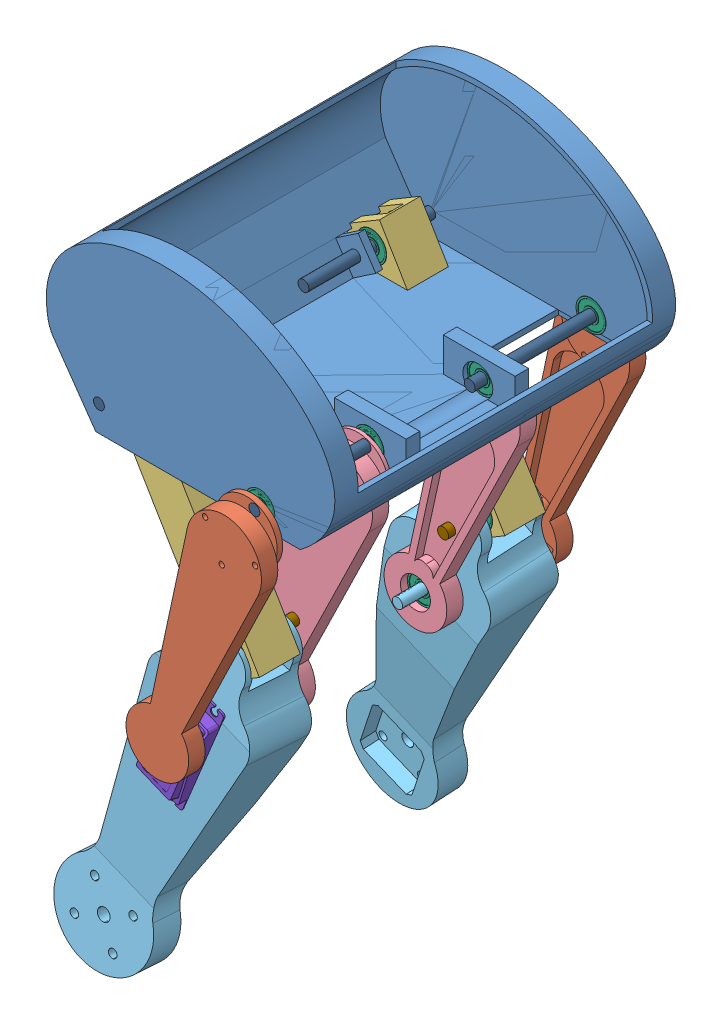
SolidWorks assembly assem2, configuration Default. Lengths in mm.
Overall size (235.71 499.1 282).
34 component instances, 10 part files, 44 mates.
Components (placement in the parent):
- head2-1: head2 [Default] at (68.1792 80.6279 71.4777) size (224.14 133.43 250)
- upleg_outer-1: upleg_outer [Default] at (100.6037 54.0653 55.4777) x (0.325909 0.945401 0) z (0 0 1) size (209.32 55 16)
- rod2-1: rod2 [Default] at (40.0387 -3.846 101.9168) x (-0.511098 0.859523 0) z (0.859523 0.511098 0) size (180 30 30)
- upleg_inner-1: upleg_inner [Default] at (100.4545 54.0549 135.5333) x (0.329052 0.944312 0) z (0 0 1) size (209.32 55 16)
- upleg_inner-2: upleg_inner [Default] at (100.4545 54.0549 255.937) x (0.329052 0.944312 0) z (0 0 -1) size (209.32 55 16)
- lowerleg2-1: lowerleg2 [Default] at (-10.3698 -235.5061 117.5405) x (-0.924718 0.380654 0) z (0.042832 0.104052 -0.993649) size (78.06 261.21 79.23)
- Bearing, Sealed, 608-2RS, 22X8X7-1: Bearing, Sealed, 608-2RS, 22X8X7 [Default] at (54.287 -78.436 247.312) x (0 0 1) z (-0.94306 -0.332623 0) size (7 22 22)
- Bearing, Sealed, 608-2RS, 22X8X7-2: Bearing, Sealed, 608-2RS, 22X8X7 [Default] at (73.7413 -31.1758 118.0588) x (0 0 1) z (0.999634 -0.027042 0) size (7 22 22)
- Bearing, Sealed, 608-2RS, 22X8X7-3: Bearing, Sealed, 608-2RS, 22X8X7 [Default] at (73.7413 -31.1758 94.9338) x (0 0 -1) z (0.30577 0.952105 0) size (7 22 22)
- Bearing, Sealed, 608-2RS, 22X8X7-4: Bearing, Sealed, 608-2RS, 22X8X7 [Default] at (54.287 -78.436 139.0333) x (0 0 -1) z (-0.978141 0.207944 0) size (7 22 22)
- ServoAttacment1-1: ServoAttacment1 [Varsayılan] at (54.8772 -78.5784 63.4777) x (-0.99957 0.029327 0) z (0 0 -1) size (37.5 37.5 6)
- DSSERVO_150kg_80kg_60kg.step-1: DSSERVO_150kg_80kg_60kg.step [Default] at (47.4545 -96.6104 117.1777) x (0.380654 0.924718 0) z (-0.924718 0.380654 0) size (87.5 54.7 30)
- lowerleg2-2: lowerleg2 [Default] at (-10.3698 -235.5061 275.4149) x (0.924718 -0.380654 0) z (0.042832 0.104052 0.993649) size (78.06 261.21 79.23)
- DSSERVO_150kg_80kg_60kg.step-2: DSSERVO_150kg_80kg_60kg.step [Default] at (47.4545 -96.6104 275.7777) x (0.380654 0.924718 0) z (0.924718 -0.380654 0) size (87.5 54.7 30)
- upleg_outer-4: upleg_outer [Default] at (100.6037 54.0653 337.4777) x (0.325909 0.945401 0) z (0 0 -1) size (209.32 55 16)
- ServoAttacment1-2: ServoAttacment1 [Varsayılan] at (54.8772 -78.5784 329.4777) x (-0.99957 0.029327 0) z (0 0 1) size (37.5 37.5 6)
- head2-2: head2 [Default] at (68.1792 80.6279 71.4777) size (224.14 133.43 250)
- ball rod-1: ball rod [Default] at (73.7413 -31.1758 86.7586) x (0.949707 0.31314 0) z (0 0 1) size (8 8 60)
- Bearing, Sealed, 608-2RS, 22X8X7-7: Bearing, Sealed, 608-2RS, 22X8X7 [Default] at (-3.9455 99.4716 94.8088) x (0 0 1) z (-1 0 0) size (7 22 22)
- Bearing, Sealed, 608-2RS, 22X8X7-8: Bearing, Sealed, 608-2RS, 22X8X7 [Default] at (-3.9455 99.4716 118.0588) x (0 0 1) z (-1 0 0) size (7 22 22)
- ball rod2-1: ball rod2 [Default] at (-3.9455 99.4716 71.4777) x (0.674488 -0.738286 0) z (0 0 1) size (8 8 100)
- Bearing, Sealed, 608-2RS, 22X8X7-9: Bearing, Sealed, 608-2RS, 22X8X7 [Default] at (114.0698 93.1279 75.1027) x (0 0 -1) z (0.914822 -0.403858 0) size (7 22 22)
- Bearing, Sealed, 608-2RS, 22X8X7-10: Bearing, Sealed, 608-2RS, 22X8X7 [Default] at (114.0698 93.1279 154.9083) x (0 0 -1) z (0.999997 0.002549 0) size (7 22 22)
- rod2-3: rod2 [Default] at (65.8244 11.4869 291.0386) x (-0.511098 0.859523 0) z (-0.859523 -0.511098 0) size (180 30 30)
- ball rod2-2: ball rod2 [Default] at (-3.9455 99.4716 221.4777) x (0.674488 -0.738286 0) z (0 0 1) size (8 8 100)
- Bearing, Sealed, 608-2RS, 22X8X7-11: Bearing, Sealed, 608-2RS, 22X8X7 [Default] at (54.287 -78.436 253.9221) x (0 0 1) z (0.978141 -0.207944 0) size (7 22 22)
- Bearing, Sealed, 608-2RS, 22X8X7-12: Bearing, Sealed, 608-2RS, 22X8X7 [Default] at (73.7413 -31.1758 274.8965) x (0 0 -1) z (-0.999634 0.027042 0) size (7 22 22)
- ball rod-2: ball rod [Default] at (73.7413 -31.1758 246.1968) x (0.949707 0.31314 0) z (0 0 1) size (8 8 60)
- Bearing, Sealed, 608-2RS, 22X8X7-13: Bearing, Sealed, 608-2RS, 22X8X7 [Default] at (-3.9455 99.4716 298.1465) x (0 0 -1) z (1 0 0) size (7 22 22)
- Bearing, Sealed, 608-2RS, 22X8X7-14: Bearing, Sealed, 608-2RS, 22X8X7 [Default] at (-3.9455 99.4716 274.8965) x (0 0 -1) z (1 0 0) size (7 22 22)
- Bearing, Sealed, 608-2RS, 22X8X7-15: Bearing, Sealed, 608-2RS, 22X8X7 [Default] at (114.0698 93.1279 317.8527) x (0 0 1) z (-0.914822 0.403858 0) size (7 22 22)
- Bearing, Sealed, 608-2RS, 22X8X7-16: Bearing, Sealed, 608-2RS, 22X8X7 [Default] at (114.0698 93.1279 238.0471) x (0 0 1) z (-0.999997 -0.002549 0) size (7 22 22)
- ball rod2-3: ball rod2 [Default] at (114.0698 93.1279 67.4777) x (0.911931 -0.410344 0) z (0 0 1) size (8 8 100)
- ball rod2-4: ball rod2 [Default] at (114.0698 93.1279 225.4777) x (0.911931 -0.410344 0) z (0 0 1) size (8 8 100)
Mates (geometry in assembly coordinates):
- Concentric4: concentric aligned: cylinder of upleg_inner-2 through (54.287 -78.436 255.937) axis (0 0 -1) radius 11; cylinder of Bearing, Sealed, 608-2RS, 22X8X7-1 through (54.287 -78.436 243.812) axis (0 0 -1) radius 4
- Coincident19: coincident aligned: circle of upleg_inner-2; circle of Bearing, Sealed, 608-2RS, 22X8X7-1
- Concentric5: concentric aligned: cylinder of rod2-1 through (73.7413 -31.1758 91.4338) axis (0 0 1) radius 11; cylinder of Bearing, Sealed, 608-2RS, 22X8X7-3 through (73.7413 -31.1758 98.4338) axis (0 0 1) radius 4
- Coincident20: coincident anti-aligned: circle of rod2-1; plane of Bearing, Sealed, 608-2RS, 22X8X7-3 through (64.5773 -28.2328 91.4338) normal (0 0 -1)
- Concentric12: concentric aligned: circle of upleg_inner-2; circle of Bearing, Sealed, 608-2RS, 22X8X7-1
- Concentric23: concentric aligned: cylinder of upleg_inner-1 through (54.287 -78.436 135.5333) axis (0 0 1) radius 11; cylinder of Bearing, Sealed, 608-2RS, 22X8X7-4 through (54.287 -78.436 142.5333) axis (0 0 1) radius 4
- Coincident26: coincident anti-aligned: circle of upleg_inner-1; plane of Bearing, Sealed, 608-2RS, 22X8X7-4 through (52.2856 -87.8506 135.5333) normal (0 0 -1)
- Concentric28: concentric anti-aligned: line of rod2-1 through (73.7413 -31.1758 91.4338) axis (0 0 1); axis of Bearing, Sealed, 608-2RS, 22X8X7-2 through (73.7413 -31.1758 114.8088) axis (0 0 -1)
- Coincident28: coincident aligned: circle of rod2-1; circle of Bearing, Sealed, 608-2RS, 22X8X7-2
- Concentric32: concentric aligned: circle of upleg_outer-1; circle of ServoAttacment1-1
- Coincident44: coincident anti-aligned: plane of lowerleg2-1 through (-10.3698 -235.5061 117.1777) normal (0 0 -1); plane of DSSERVO_150kg_80kg_60kg.step-1 through (47.4545 -96.6104 117.1777) normal (0 0 1)
- Coincident46: coincident anti-aligned: plane of lowerleg2-1 through (73.566 -72.3213 117.1777) normal (-0.380654 -0.924718 0); plane of DSSERVO_150kg_80kg_60kg.step-1 through (71.809 -71.5981 106.4777) normal (0.380654 0.924718 0)
- Coincident47: coincident: line of lowerleg2-1 through (73.566 -72.3213 83.1777) axis (-0.380654 -0.924718 0); plane of DSSERVO_150kg_80kg_60kg.step-1 through (71.7008 -76.8524 106.4777) normal (0.924718 -0.380654 0)
- Coincident53: coincident anti-aligned: plane of ServoAttacment1-1 through (54.8772 -78.5784 67.4777) normal (0 0 1); circle of DSSERVO_150kg_80kg_60kg.step-1
- Parallel12: parallel anti-aligned: plane of ServoAttacment1-1 through (54.8772 -78.5784 63.4777) normal (0 0 1); plane of DSSERVO_150kg_80kg_60kg.step-1 through (54.8772 -78.5784 62.4777) normal (0 0 -1)
- Concentric46: concentric anti-aligned: cylinder of ServoAttacment1-1 through (54.8772 -78.5784 67.4777) axis (0 0 -1) radius 3; cylinder of DSSERVO_150kg_80kg_60kg.step-1 through (54.8772 -78.5784 62.4777) axis (0 0 1) radius 3.9
- Concentric62: concentric anti-aligned: cylinder of Bearing, Sealed, 608-2RS, 22X8X7-1 through (54.287 -78.436 243.812) axis (0 0 -1) radius 4; cylinder of lowerleg2-2 through (54.287 -78.436 232.2207) axis (0 0 1) radius 3.775
- Coincident66: coincident anti-aligned: plane of head2-1 through (83.1964 205.2713 71.4777) normal (0 0 -1); circle of upleg_outer-1
- Concentric63: concentric anti-aligned: cylinder of Bearing, Sealed, 608-2RS, 22X8X7-3 through (73.7413 -31.1758 98.4338) axis (0 0 1) radius 4; line of lowerleg2-1 through (73.7413 -31.1758 91.99) axis (0 0 -1)
- Concentric66: concentric aligned: cylinder of Bearing, Sealed, 608-2RS, 22X8X7-2 through (73.7413 -31.1758 114.5588) axis (0 0 -1) radius 4; cylinder of ball rod-1 through (73.7413 -31.1758 146.7586) axis (0 0 -1) radius 4
- Concentric67: concentric anti-aligned: circle of Bearing, Sealed, 608-2RS, 22X8X7-2; circle of ball rod-1
- Concentric68: concentric aligned: circle of Bearing, Sealed, 608-2RS, 22X8X7-3; circle of ball rod-1
- Concentric69: concentric aligned: cylinder of lowerleg2-1 through (73.7413 -31.1758 138.6213) axis (0 0 -1) radius 4; cylinder of ball rod-1 through (73.7413 -31.1758 146.7586) axis (0 0 -1) radius 4
- Concentric70: concentric aligned: cylinder of lowerleg2-1 through (73.7413 -31.1758 138.6213) axis (0 0 -1) radius 4; cylinder of ball rod-1 through (73.7413 -31.1758 146.7586) axis (0 0 -1) radius 4
- Tangent1: tangent: curve of lowerleg2-1; circle of ball rod-1
- Concentric73: concentric anti-aligned: cylinder of lowerleg2-1 through (54.287 -78.436 160.7346) axis (0 0 -1) radius 3.775; cylinder of Bearing, Sealed, 608-2RS, 22X8X7-4 through (54.287 -78.436 142.5333) axis (0 0 1) radius 4
- Tangent4: tangent: curve of lowerleg2-1; plane of Bearing, Sealed, 608-2RS, 22X8X7-3 through (64.6963 -28.271 91.6838) normal (0 0 -1)
- Concentric76: concentric anti-aligned: cylinder of rod2-1 through (-3.9455 99.4716 91.4338) axis (0 0 1) radius 11; cylinder of Bearing, Sealed, 608-2RS, 22X8X7-7 through (-3.9455 99.4716 91.3088) axis (0 0 -1) radius 11
- Coincident77: coincident anti-aligned: circle of rod2-1; circle of Bearing, Sealed, 608-2RS, 22X8X7-7
- Concentric77: concentric anti-aligned: cylinder of rod2-1 through (-3.9455 99.4716 91.4338) axis (0 0 1) radius 11; cylinder of Bearing, Sealed, 608-2RS, 22X8X7-8 through (-3.9455 99.4716 114.5588) axis (0 0 -1) radius 11
- Coincident78: coincident anti-aligned: cone of rod2-1; cone of Bearing, Sealed, 608-2RS, 22X8X7-8 through (-3.9455 99.4716 121.5588) axis (0 0 1)
- Concentric81: concentric aligned: cylinder of head2-1 through (-3.9455 99.4716 321.4777) axis (0 0 -1) radius 4; cylinder of ball rod2-1 through (-3.9455 99.4716 171.4777) axis (0 0 -1) radius 4
- Coincident82: coincident anti-aligned: circle of head2-2; circle of ball rod2-1
- Concentric82: concentric aligned: cylinder of Bearing, Sealed, 608-2RS, 22X8X7-7 through (-3.9455 99.4716 91.3088) axis (0 0 -1) radius 4; cylinder of ball rod2-1 through (-3.9455 99.4716 171.4777) axis (0 0 -1) radius 4
- Concentric83: concentric aligned: cylinder of head2-1 through (114.0698 93.1279 71.4777) axis (0 0 1) radius 11; cylinder of Bearing, Sealed, 608-2RS, 22X8X7-9 through (114.0698 93.1279 78.6027) axis (0 0 1) radius 11
- Coincident84: coincident anti-aligned: circle of head2-2; circle of Bearing, Sealed, 608-2RS, 22X8X7-9
- Concentric86: concentric aligned: cylinder of upleg_outer-1 through (114.0698 93.1279 55.4777) axis (0 0 1) radius 4; cylinder of Bearing, Sealed, 608-2RS, 22X8X7-9 through (114.0698 93.1279 78.6027) axis (0 0 1) radius 4
- Concentric87: concentric aligned: cylinder of head2-1 through (114.0698 93.1279 71.4777) axis (0 0 1) radius 11; cylinder of Bearing, Sealed, 608-2RS, 22X8X7-10 through (114.0698 93.1279 158.4083) axis (0 0 1) radius 11
- Coincident85: coincident anti-aligned: circle of head2-2; circle of Bearing, Sealed, 608-2RS, 22X8X7-10
- Concentric90: concentric aligned: cylinder of upleg_inner-1 through (114.0698 93.1279 135.5333) axis (0 0 1) radius 4; cylinder of Bearing, Sealed, 608-2RS, 22X8X7-10 through (114.0698 93.1279 158.4083) axis (0 0 1) radius 4
- Concentric91: concentric aligned: cylinder of upleg_inner-2 through (114.0698 93.1279 255.937) axis (0 0 -1) radius 4; cylinder of Bearing, Sealed, 608-2RS, 22X8X7-16 through (114.0698 93.1279 234.5471) axis (0 0 -1) radius 4
- Concentric92: concentric anti-aligned: circle of upleg_inner-1; cylinder of ball rod2-3 through (114.0698 93.1279 167.4777) axis (0 0 -1) radius 4
- Coincident93: coincident aligned: plane of upleg_outer-1 through (100.6037 54.0653 63.4777) normal (0 0 1); plane of ServoAttacment1-1 through (54.8772 -78.5784 63.4777) normal (0 0 1)
- Coincident94: coincident anti-aligned: circle of upleg_inner-1; plane of head2-2 through (141.3425 74.6279 151.5333) normal (0 0 -1)
